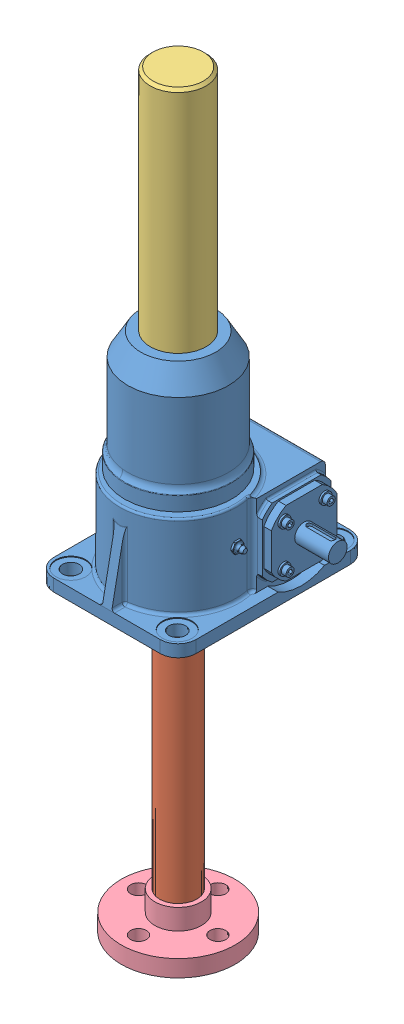
SolidWorks assembly EM5_BSJ_I_6_1_SSE_1_SSE_2_FP_200_S, configuration Valor predeterminado. Lengths in mm.
Overall size (230.69 802.52 203.61).
4 component instances, 4 part files, 5 mates.
Components (placement in the parent):
- housing_I-SSE-SSE_1-1: housing_I-SSE-SSE_1 [Valor predeterminado] at origin size (230.69 251.64 203.61)
- UILiftShaft_5-BSJ-I-1: UILiftShaft_5-BSJ-I [Valor predeterminado] at (0 182.9177 0) x (-0.031165 0 -0.999514) z (0 1 0) size (43 43 507.6)
- UIStemCover_5-BSJ-I-1: UIStemCover_5-BSJ-I [Valor predeterminado] at (0 232.8413 0) x (0.954524 0 0.298134) z (0 1 0) size (60 60 245)
- Top-Plate_5-BSJ-I-1: Top-Plate_5-BSJ-I [Valor predeterminado] at (0 -306.6825 0) x (0 1 0) z (-1 0 0) size (40 122 122)
Mates (geometry in assembly coordinates):
- Concêntrico1: concentric aligned: cylinder of UILiftShaft_5-BSJ-I-1 through (0 182.9177 0) axis (0 -1 0) radius 12.5; cylinder of Top-Plate_5-BSJ-I-1 through (0 -323.642 0) axis (0 -1 0) radius 25
- Coincidente1: coincident anti-aligned: plane of UILiftShaft_5-BSJ-I-1 through (-19.9903 -284.6825 0.6233) normal (0 -1 0); plane of Top-Plate_5-BSJ-I-1 through (0 -284.6825 -25) normal (0 1 0)
- Concêntrico2: concentric aligned: cylinder of housing_I-SSE-SSE_1-1 through (0 232.8413 0) axis (0 -1 0) radius 20.25; cylinder of UILiftShaft_5-BSJ-I-1 through (0 182.9177 0) axis (0 -1 0) radius 20
- Concêntrico4: concentric anti-aligned: cylinder of UILiftShaft_5-BSJ-I-1 through (0 182.9177 0) axis (0 -1 0) radius 20; cylinder of UIStemCover_5-BSJ-I-1 through (0 232.8413 0) axis (0 1 0) radius 30
- Tangente3: tangent: cone of housing_I-SSE-SSE_1-1 through (0 232.817 0) axis (0 1 -0.000604); circle of UIStemCover_5-BSJ-I-1
